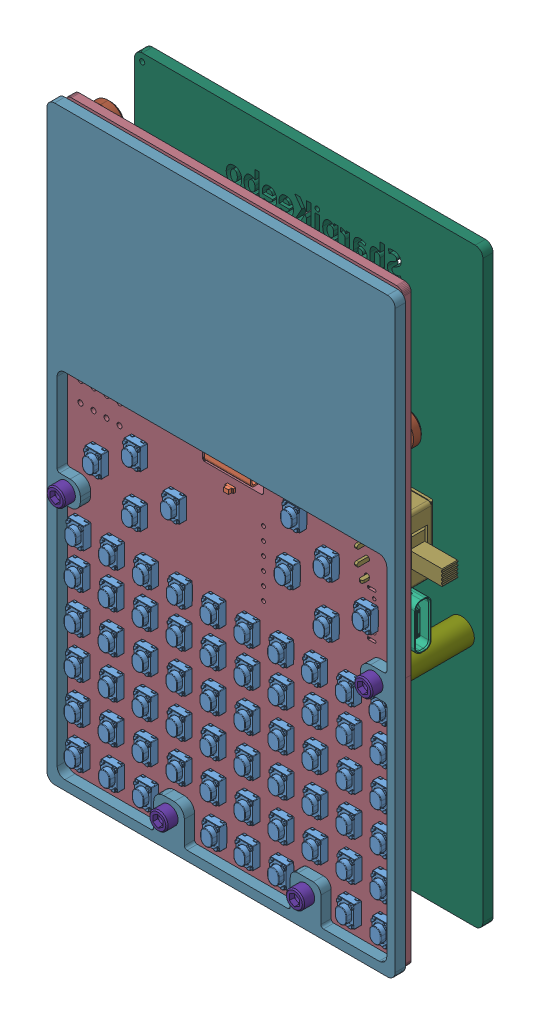
SolidWorks assembly pcbframe, configuration Défaut. Lengths in mm.
Overall size (72.24 115.41 21.31).
366 component instances, 20 part files, 22 mates.
Components (placement in the parent):
- pcbframe.STEP-1: pcbframe.STEP [Défaut] at origin size (71.24 115.32 9.7)
  - pcbframe.step.STEP-1: pcbframe.step.STEP [Défaut] at origin size (71.24 115.32 9.7)
    - SKRPABE010.step.STEP-1: SKRPABE010.step.STEP [Défaut] at (152.039 -127.29 1.65) x (0 1 0) z (1 0 0) size (4.6 2.5 3.2)
      - SOLID.step.STEP-1: SOLID.step.STEP [Défaut] at origin size (4.6 2.5 3.2)
    - SKRPABE010.step.STEP-2: SKRPABE010.step.STEP [Défaut] at (158.671 -127.29 1.65) x (0 1 0) z (1 0 0) size (4.6 2.5 3.2)
      - SOLID.step.STEP-1: SOLID.step.STEP [Défaut] at origin size (4.6 2.5 3.2)
    - SKRPABE010.step.STEP-3: SKRPABE010.step.STEP [Défaut] at (165.303 -127.29 1.65) x (0 1 0) z (1 0 0) size (4.6 2.5 3.2)
      - SOLID.step.STEP-1: SOLID.step.STEP [Défaut] at origin size (4.6 2.5 3.2)
    - SKRPABE010.step.STEP-4: SKRPABE010.step.STEP [Défaut] at (171.936 -127.29 1.65) x (0 1 0) z (1 0 0) size (4.6 2.5 3.2)
      - SOLID.step.STEP-1: SOLID.step.STEP [Défaut] at origin size (4.6 2.5 3.2)
    - SKRPABE010.step.STEP-5: SKRPABE010.step.STEP [Défaut] at (178.568 -127.29 1.65) x (0 1 0) z (1 0 0) size (4.6 2.5 3.2)
      - SOLID.step.STEP-1: SOLID.step.STEP [Défaut] at origin size (4.6 2.5 3.2)
    - SKRPABE010.step.STEP-6: SKRPABE010.step.STEP [Défaut] at (185.2 -127.29 1.65) x (0 1 0) z (1 0 0) size (4.6 2.5 3.2)
      - SOLID.step.STEP-1: SOLID.step.STEP [Défaut] at origin size (4.6 2.5 3.2)
    - SKRPABE010.step.STEP-7: SKRPABE010.step.STEP [Défaut] at (191.832 -127.29 1.65) x (0 1 0) z (1 0 0) size (4.6 2.5 3.2)
      - SOLID.step.STEP-1: SOLID.step.STEP [Défaut] at origin size (4.6 2.5 3.2)
    - SKRPABE010.step.STEP-8: SKRPABE010.step.STEP [Défaut] at (198.465 -127.29 1.65) x (0 1 0) z (1 0 0) size (4.6 2.5 3.2)
      - SOLID.step.STEP-1: SOLID.step.STEP [Défaut] at origin size (4.6 2.5 3.2)
    - SKRPABE010.step.STEP-9: SKRPABE010.step.STEP [Défaut] at (205.097 -127.29 1.65) x (0 1 0) z (1 0 0) size (4.6 2.5 3.2)
      - SOLID.step.STEP-1: SOLID.step.STEP [Défaut] at origin size (4.6 2.5 3.2)
    - SKRPABE010.step.STEP-10: SKRPABE010.step.STEP [Défaut] at (200.68 -101.255 1.65) x (0 1 0) z (1 0 0) size (4.6 2.5 3.2)
      - SOLID.step.STEP-1: SOLID.step.STEP [Défaut] at origin size (4.6 2.5 3.2)
    - SKRPABE010.step.STEP-11: SKRPABE010.step.STEP [Défaut] at (200.68 -111.415 1.65) x (0 1 0) z (1 0 0) size (4.6 2.5 3.2)
      - SOLID.step.STEP-1: SOLID.step.STEP [Défaut] at origin size (4.6 2.5 3.2)
    - SKRPABE010.step.STEP-12: SKRPABE010.step.STEP [Défaut] at (152.039 -134.91 1.65) x (0 1 0) z (1 0 0) size (4.6 2.5 3.2)
      - SOLID.step.STEP-1: SOLID.step.STEP [Défaut] at origin size (4.6 2.5 3.2)
    - SKRPABE010.step.STEP-13: SKRPABE010.step.STEP [Défaut] at (158.671 -134.91 1.65) x (0 1 0) z (1 0 0) size (4.6 2.5 3.2)
      - SOLID.step.STEP-1: SOLID.step.STEP [Défaut] at origin size (4.6 2.5 3.2)
    - SKRPABE010.step.STEP-14: SKRPABE010.step.STEP [Défaut] at (165.303 -134.91 1.65) x (0 1 0) z (1 0 0) size (4.6 2.5 3.2)
      - SOLID.step.STEP-1: SOLID.step.STEP [Défaut] at origin size (4.6 2.5 3.2)
    - SKRPABE010.step.STEP-15: SKRPABE010.step.STEP [Défaut] at (171.936 -134.91 1.65) x (0 1 0) z (1 0 0) size (4.6 2.5 3.2)
      - SOLID.step.STEP-1: SOLID.step.STEP [Défaut] at origin size (4.6 2.5 3.2)
    - SKRPABE010.step.STEP-16: SKRPABE010.step.STEP [Défaut] at (178.568 -134.91 1.65) x (0 1 0) z (1 0 0) size (4.6 2.5 3.2)
      - SOLID.step.STEP-1: SOLID.step.STEP [Défaut] at origin size (4.6 2.5 3.2)
    - SKRPABE010.step.STEP-17: SKRPABE010.step.STEP [Défaut] at (185.2 -134.91 1.65) x (0 1 0) z (1 0 0) size (4.6 2.5 3.2)
      - SOLID.step.STEP-1: SOLID.step.STEP [Défaut] at origin size (4.6 2.5 3.2)
    - SKRPABE010.step.STEP-18: SKRPABE010.step.STEP [Défaut] at (191.832 -134.91 1.65) x (0 1 0) z (1 0 0) size (4.6 2.5 3.2)
      - SOLID.step.STEP-1: SOLID.step.STEP [Défaut] at origin size (4.6 2.5 3.2)
    - SKRPABE010.step.STEP-19: SKRPABE010.step.STEP [Défaut] at (198.465 -134.91 1.65) x (0 1 0) z (1 0 0) size (4.6 2.5 3.2)
      - SOLID.step.STEP-1: SOLID.step.STEP [Défaut] at origin size (4.6 2.5 3.2)
    - SKRPABE010.step.STEP-20: SKRPABE010.step.STEP [Défaut] at (205.097 -134.91 1.65) x (0 1 0) z (1 0 0) size (4.6 2.5 3.2)
      - SOLID.step.STEP-1: SOLID.step.STEP [Défaut] at origin size (4.6 2.5 3.2)
    - SKRPABE010.step.STEP-21: SKRPABE010.step.STEP [Défaut] at (211.729 -134.91 1.65) x (0 1 0) z (1 0 0) size (4.6 2.5 3.2)
      - SOLID.step.STEP-1: SOLID.step.STEP [Défaut] at origin size (4.6 2.5 3.2)
    - SKRPABE010.step.STEP-22: SKRPABE010.step.STEP [Défaut] at (193.06 -106.335 1.65) x (0 1 0) z (1 0 0) size (4.6 2.5 3.2)
      - SOLID.step.STEP-1: SOLID.step.STEP [Défaut] at origin size (4.6 2.5 3.2)
    - SKRPABE010.step.STEP-23: SKRPABE010.step.STEP [Défaut] at (208.3 -106.335 1.65) x (0 1 0) z (1 0 0) size (4.6 2.5 3.2)
      - SOLID.step.STEP-1: SOLID.step.STEP [Défaut] at origin size (4.6 2.5 3.2)
    - SKRPABE010.step.STEP-24: SKRPABE010.step.STEP [Défaut] at (152.039 -142.53 1.65) x (0 1 0) z (1 0 0) size (4.6 2.5 3.2)
      - SOLID.step.STEP-1: SOLID.step.STEP [Défaut] at origin size (4.6 2.5 3.2)
    - SKRPABE010.step.STEP-25: SKRPABE010.step.STEP [Défaut] at (158.671 -142.53 1.65) x (0 1 0) z (1 0 0) size (4.6 2.5 3.2)
      - SOLID.step.STEP-1: SOLID.step.STEP [Défaut] at origin size (4.6 2.5 3.2)
    - SKRPABE010.step.STEP-26: SKRPABE010.step.STEP [Défaut] at (165.303 -142.53 1.65) x (0 1 0) z (1 0 0) size (4.6 2.5 3.2)
      - SOLID.step.STEP-1: SOLID.step.STEP [Défaut] at origin size (4.6 2.5 3.2)
    - SKRPABE010.step.STEP-27: SKRPABE010.step.STEP [Défaut] at (171.936 -142.53 1.65) x (0 1 0) z (1 0 0) size (4.6 2.5 3.2)
      - SOLID.step.STEP-1: SOLID.step.STEP [Défaut] at origin size (4.6 2.5 3.2)
    - SKRPABE010.step.STEP-28: SKRPABE010.step.STEP [Défaut] at (185.2 -142.53 1.65) x (0 1 0) z (1 0 0) size (4.6 2.5 3.2)
      - SOLID.step.STEP-1: SOLID.step.STEP [Défaut] at origin size (4.6 2.5 3.2)
    - SKRPABE010.step.STEP-29: SKRPABE010.step.STEP [Défaut] at (191.832 -142.53 1.65) x (0 1 0) z (1 0 0) size (4.6 2.5 3.2)
      - SOLID.step.STEP-1: SOLID.step.STEP [Défaut] at origin size (4.6 2.5 3.2)
    - SKRPABE010.step.STEP-30: SKRPABE010.step.STEP [Défaut] at (198.465 -142.53 1.65) x (0 1 0) z (1 0 0) size (4.6 2.5 3.2)
      - SOLID.step.STEP-1: SOLID.step.STEP [Défaut] at origin size (4.6 2.5 3.2)
    - SKRPABE010.step.STEP-31: SKRPABE010.step.STEP [Défaut] at (205.097 -142.53 1.65) x (0 1 0) z (1 0 0) size (4.6 2.5 3.2)
      - SOLID.step.STEP-1: SOLID.step.STEP [Défaut] at origin size (4.6 2.5 3.2)
    - SKRPABE010.step.STEP-32: SKRPABE010.step.STEP [Défaut] at (211.729 -142.53 1.65) x (0 1 0) z (1 0 0) size (4.6 2.5 3.2)
      - SOLID.step.STEP-1: SOLID.step.STEP [Défaut] at origin size (4.6 2.5 3.2)
    - SKRPABE010.step.STEP-33: SKRPABE010.step.STEP [Défaut] at (185.186 -120.178 1.65) x (0 1 0) z (1 0 0) size (4.6 2.5 3.2)
      - SOLID.step.STEP-1: SOLID.step.STEP [Défaut] at origin size (4.6 2.5 3.2)
    - SKRPABE010.step.STEP-34: SKRPABE010.step.STEP [Défaut] at (191.79 -120.178 1.65) x (0 1 0) z (1 0 0) size (4.6 2.5 3.2)
      - SOLID.step.STEP-1: SOLID.step.STEP [Défaut] at origin size (4.6 2.5 3.2)
    - SKRPABE010.step.STEP-35: SKRPABE010.step.STEP [Défaut] at (152.039 -150.15 1.65) x (0 1 0) z (1 0 0) size (4.6 2.5 3.2)
      - SOLID.step.STEP-1: SOLID.step.STEP [Défaut] at origin size (4.6 2.5 3.2)
    - SKRPABE010.step.STEP-36: SKRPABE010.step.STEP [Défaut] at (158.671 -150.15 1.65) x (0 1 0) z (1 0 0) size (4.6 2.5 3.2)
      - SOLID.step.STEP-1: SOLID.step.STEP [Défaut] at origin size (4.6 2.5 3.2)
    - SKRPABE010.step.STEP-37: SKRPABE010.step.STEP [Défaut] at (165.303 -150.15 1.65) x (0 1 0) z (1 0 0) size (4.6 2.5 3.2)
      - SOLID.step.STEP-1: SOLID.step.STEP [Défaut] at origin size (4.6 2.5 3.2)
    - SKRPABE010.step.STEP-38: SKRPABE010.step.STEP [Défaut] at (171.936 -150.15 1.65) x (0 1 0) z (1 0 0) size (4.6 2.5 3.2)
      - SOLID.step.STEP-1: SOLID.step.STEP [Défaut] at origin size (4.6 2.5 3.2)
    - SKRPABE010.step.STEP-39: SKRPABE010.step.STEP [Défaut] at (178.568 -150.15 1.65) x (0 1 0) z (1 0 0) size (4.6 2.5 3.2)
      - SOLID.step.STEP-1: SOLID.step.STEP [Défaut] at origin size (4.6 2.5 3.2)
    - SKRPABE010.step.STEP-40: SKRPABE010.step.STEP [Défaut] at (185.2 -150.15 1.65) x (0 1 0) z (1 0 0) size (4.6 2.5 3.2)
      - SOLID.step.STEP-1: SOLID.step.STEP [Défaut] at origin size (4.6 2.5 3.2)
    - SKRPABE010.step.STEP-41: SKRPABE010.step.STEP [Défaut] at (191.832 -150.15 1.65) x (0 1 0) z (1 0 0) size (4.6 2.5 3.2)
      - SOLID.step.STEP-1: SOLID.step.STEP [Défaut] at origin size (4.6 2.5 3.2)
    - SKRPABE010.step.STEP-42: SKRPABE010.step.STEP [Défaut] at (198.465 -150.15 1.65) x (0 1 0) z (1 0 0) size (4.6 2.5 3.2)
      - SOLID.step.STEP-1: SOLID.step.STEP [Défaut] at origin size (4.6 2.5 3.2)
    - SKRPABE010.step.STEP-43: SKRPABE010.step.STEP [Défaut] at (205.097 -150.15 1.65) x (0 1 0) z (1 0 0) size (4.6 2.5 3.2)
      - SOLID.step.STEP-1: SOLID.step.STEP [Défaut] at origin size (4.6 2.5 3.2)
    - SKRPABE010.step.STEP-44: SKRPABE010.step.STEP [Défaut] at (211.729 -150.15 1.65) x (0 1 0) z (1 0 0) size (4.6 2.5 3.2)
      - SOLID.step.STEP-1: SOLID.step.STEP [Défaut] at origin size (4.6 2.5 3.2)
    - SKRPABE010.step.STEP-45: SKRPABE010.step.STEP [Défaut] at (198.394 -120.178 1.65) x (0 1 0) z (1 0 0) size (4.6 2.5 3.2)
      - SOLID.step.STEP-1: SOLID.step.STEP [Défaut] at origin size (4.6 2.5 3.2)
    - SKRPABE010.step.STEP-46: SKRPABE010.step.STEP [Défaut] at (204.998 -120.178 1.65) x (0 1 0) z (1 0 0) size (4.6 2.5 3.2)
      - SOLID.step.STEP-1: SOLID.step.STEP [Défaut] at origin size (4.6 2.5 3.2)
    - SKRPABE010.step.STEP-47: SKRPABE010.step.STEP [Défaut] at (152.039 -157.77 1.65) x (0 1 0) z (1 0 0) size (4.6 2.5 3.2)
      - SOLID.step.STEP-1: SOLID.step.STEP [Défaut] at origin size (4.6 2.5 3.2)
    - SKRPABE010.step.STEP-48: SKRPABE010.step.STEP [Défaut] at (158.77 -157.77 1.65) x (0 1 0) z (1 0 0) size (4.6 2.5 3.2)
      - SOLID.step.STEP-1: SOLID.step.STEP [Défaut] at origin size (4.6 2.5 3.2)
    - SKRPABE010.step.STEP-49: SKRPABE010.step.STEP [Défaut] at (165.374 -157.77 1.65) x (0 1 0) z (1 0 0) size (4.6 2.5 3.2)
      - SOLID.step.STEP-1: SOLID.step.STEP [Défaut] at origin size (4.6 2.5 3.2)
    - SKRPABE010.step.STEP-50: SKRPABE010.step.STEP [Défaut] at (178.709 -157.77 1.65) x (0 1 0) z (1 0 0) size (4.6 2.5 3.2)
      - SOLID.step.STEP-1: SOLID.step.STEP [Défaut] at origin size (4.6 2.5 3.2)
    - SKRPABE010.step.STEP-51: SKRPABE010.step.STEP [Défaut] at (185.186 -157.77 1.65) x (0 1 0) z (1 0 0) size (4.6 2.5 3.2)
      - SOLID.step.STEP-1: SOLID.step.STEP [Défaut] at origin size (4.6 2.5 3.2)
    - SKRPABE010.step.STEP-52: SKRPABE010.step.STEP [Défaut] at (191.79 -157.77 1.65) x (0 1 0) z (1 0 0) size (4.6 2.5 3.2)
      - SOLID.step.STEP-1: SOLID.step.STEP [Défaut] at origin size (4.6 2.5 3.2)
    - SKRPABE010.step.STEP-53: SKRPABE010.step.STEP [Défaut] at (211.729 -157.77 1.65) x (0 1 0) z (1 0 0) size (4.6 2.5 3.2)
      - SOLID.step.STEP-1: SOLID.step.STEP [Défaut] at origin size (4.6 2.5 3.2)
    - SKRPABE010.step.STEP-54: SKRPABE010.step.STEP [Défaut] at (211.602 -120.178 1.65) x (0 1 0) z (1 0 0) size (4.6 2.5 3.2)
      - SOLID.step.STEP-1: SOLID.step.STEP [Défaut] at origin size (4.6 2.5 3.2)
    - SKRPABE010.step.STEP-55: SKRPABE010.step.STEP [Défaut] at (152.166 -120.178 1.65) x (0 1 0) z (1 0 0) size (4.6 2.5 3.2)
      - SOLID.step.STEP-1: SOLID.step.STEP [Défaut] at origin size (4.6 2.5 3.2)
    - SKRPABE010.step.STEP-56: SKRPABE010.step.STEP [Défaut] at (158.77 -120.178 1.65) x (0 1 0) z (1 0 0) size (4.6 2.5 3.2)
      - SOLID.step.STEP-1: SOLID.step.STEP [Défaut] at origin size (4.6 2.5 3.2)
    - SKRPABE010.step.STEP-57: SKRPABE010.step.STEP [Défaut] at (165.374 -120.178 1.65) x (0 1 0) z (1 0 0) size (4.6 2.5 3.2)
      - SOLID.step.STEP-1: SOLID.step.STEP [Défaut] at origin size (4.6 2.5 3.2)
    - SKRPABE010.step.STEP-58: SKRPABE010.step.STEP [Défaut] at (171.978 -120.178 1.65) x (0 1 0) z (1 0 0) size (4.6 2.5 3.2)
      - SOLID.step.STEP-1: SOLID.step.STEP [Défaut] at origin size (4.6 2.5 3.2)
    - SKRPABE010.step.STEP-59: SKRPABE010.step.STEP [Défaut] at (178.582 -120.178 1.65) x (0 1 0) z (1 0 0) size (4.6 2.5 3.2)
      - SOLID.step.STEP-1: SOLID.step.STEP [Défaut] at origin size (4.6 2.5 3.2)
    - SKRPABE010.step.STEP-60: SKRPABE010.step.STEP [Défaut] at (211.729 -127.29 1.65) x (0 1 0) z (1 0 0) size (4.6 2.5 3.2)
      - SOLID.step.STEP-1: SOLID.step.STEP [Défaut] at origin size (4.6 2.5 3.2)
    - SKRPABE010.step.STEP-61: SKRPABE010.step.STEP [Défaut] at (204.998 -157.77 1.65) x (0 1 0) z (1 0 0) size (4.6 2.5 3.2)
      - SOLID.step.STEP-1: SOLID.step.STEP [Défaut] at origin size (4.6 2.5 3.2)
    - SKRPABE010.step.STEP-62: SKRPABE010.step.STEP [Défaut] at (178.568 -142.53 1.65) x (0 1 0) z (1 0 0) size (4.6 2.5 3.2)
      - SOLID.step.STEP-1: SOLID.step.STEP [Défaut] at origin size (4.6 2.5 3.2)
    - SKRPABE010.step.STEP-63: SKRPABE010.step.STEP [Défaut] at (194.33 -96.048 1.65) x (0 1 0) z (1 0 0) size (4.6 2.5 3.2)
      - SOLID.step.STEP-1: SOLID.step.STEP [Défaut] at origin size (4.6 2.5 3.2)
    - SKRPABE010.step.STEP-64: SKRPABE010.step.STEP [Défaut] at (155.595 -106.335 1.65) x (0 1 0) z (1 0 0) size (4.6 2.5 3.2)
      - SOLID.step.STEP-1: SOLID.step.STEP [Défaut] at origin size (4.6 2.5 3.2)
    - SKRPABE010.step.STEP-65: SKRPABE010.step.STEP [Défaut] at (163.215 -111.415 1.65) x (0 1 0) z (1 0 0) size (4.6 2.5 3.2)
      - SOLID.step.STEP-1: SOLID.step.STEP [Défaut] at origin size (4.6 2.5 3.2)
    - SKRPABE010.step.STEP-66: SKRPABE010.step.STEP [Défaut] at (163.215 -101.255 1.65) x (0 1 0) z (1 0 0) size (4.6 2.5 3.2)
      - SOLID.step.STEP-1: SOLID.step.STEP [Défaut] at origin size (4.6 2.5 3.2)
    - SKRPABE010.step.STEP-67: SKRPABE010.step.STEP [Défaut] at (170.835 -106.335 1.65) x (0 1 0) z (1 0 0) size (4.6 2.5 3.2)
      - SOLID.step.STEP-1: SOLID.step.STEP [Défaut] at origin size (4.6 2.5 3.2)
    - LED_0603_1608Metric.step.STEP-1: LED_0603_1608Metric.step.STEP [Défaut] at (181.204 -98.4885 1.65) size (1.6 0.8 1.1)
      - SOLID-0.step.STEP-1: SOLID-0.step.STEP [Défaut] at origin size (1.6 0.8 1.1)
    - C_0603_1608Metric.step.STEP-1: C_0603_1608Metric.step.STEP [Défaut] at (185.42 -81.915 -0.05) x (0 1 0) z (0 0 -1) size (1.6 0.8 0.8)
      - SOLID-1.step.STEP-1: SOLID-1.step.STEP [Défaut] at origin size (1.6 0.8 0.8)
    - C_0603_1608Metric.step.STEP-2: C_0603_1608Metric.step.STEP [Défaut] at (181.61 -81.915 -0.05) x (0 1 0) z (0 0 -1) size (1.6 0.8 0.8)
      - SOLID-1.step.STEP-1: SOLID-1.step.STEP [Défaut] at origin size (1.6 0.8 0.8)
    - C_0603_1608Metric.step.STEP-3: C_0603_1608Metric.step.STEP [Défaut] at (179.705 -81.915 -0.05) x (0 1 0) z (0 0 -1) size (1.6 0.8 0.8)
      - SOLID-1.step.STEP-1: SOLID-1.step.STEP [Défaut] at origin size (1.6 0.8 0.8)
    - R_0603_1608Metric.step.STEP-1: R_0603_1608Metric.step.STEP [Défaut] at (199.39 -97.7265 -0.05) x (1 0 0) z (0 0 -1) size (1.6 0.8 0.45)
      - SOLID-2.step.STEP-1: SOLID-2.step.STEP [Défaut] at origin size (1.6 0.8 0.45)
    - R_0603_1608Metric.step.STEP-2: R_0603_1608Metric.step.STEP [Défaut] at (195.136 -106.236 -0.05) x (-1 0 0) z (0 0 -1) size (1.6 0.8 0.45)
      - SOLID-2.step.STEP-1: SOLID-2.step.STEP [Défaut] at origin size (1.6 0.8 0.45)
    - R_0603_1608Metric.step.STEP-3: R_0603_1608Metric.step.STEP [Défaut] at (170.284 -95.885 -0.05) x (1 0 0) z (0 0 -1) size (1.6 0.8 0.45)
      - SOLID-2.step.STEP-1: SOLID-2.step.STEP [Défaut] at origin size (1.6 0.8 0.45)
    - R_0603_1608Metric.step.STEP-4: R_0603_1608Metric.step.STEP [Défaut] at (152.34 -106.331 -0.05) x (-1 0 0) z (0 0 -1) size (1.6 0.8 0.45)
      - SOLID-2.step.STEP-1: SOLID-2.step.STEP [Défaut] at origin size (1.6 0.8 0.45)
    - R_0603_1608Metric.step.STEP-5: R_0603_1608Metric.step.STEP [Défaut] at (156.976 -112.872 -0.05) x (-1 0 0) z (0 0 -1) size (1.6 0.8 0.45)
      - SOLID-2.step.STEP-1: SOLID-2.step.STEP [Défaut] at origin size (1.6 0.8 0.45)
    - R_0603_1608Metric.step.STEP-6: R_0603_1608Metric.step.STEP [Défaut] at (156.865 -109.696 -0.05) x (-1 0 0) z (0 0 -1) size (1.6 0.8 0.45)
      - SOLID-2.step.STEP-1: SOLID-2.step.STEP [Défaut] at origin size (1.6 0.8 0.45)
    - R_0603_1608Metric.step.STEP-7: R_0603_1608Metric.step.STEP [Défaut] at (170.18 -93.98 -0.05) x (1 0 0) z (0 0 -1) size (1.6 0.8 0.45)
      - SOLID-2.step.STEP-1: SOLID-2.step.STEP [Défaut] at origin size (1.6 0.8 0.45)
    - R_0603_1608Metric.step.STEP-8: R_0603_1608Metric.step.STEP [Défaut] at (152.467 -103.283 -0.05) x (-1 0 0) z (0 0 -1) size (1.6 0.8 0.45)
      - SOLID-2.step.STEP-1: SOLID-2.step.STEP [Défaut] at origin size (1.6 0.8 0.45)
    - R_0603_1608Metric.step.STEP-9: R_0603_1608Metric.step.STEP [Défaut] at (156.722 -106.268 -0.05) x (-1 0 0) z (0 0 -1) size (1.6 0.8 0.45)
      - SOLID-2.step.STEP-1: SOLID-2.step.STEP [Défaut] at origin size (1.6 0.8 0.45)
    - R_0603_1608Metric.step.STEP-10: R_0603_1608Metric.step.STEP [Défaut] at (156.785 -103.283 -0.05) x (-1 0 0) z (0 0 -1) size (1.6 0.8 0.45)
      - SOLID-2.step.STEP-1: SOLID-2.step.STEP [Défaut] at origin size (1.6 0.8 0.45)
    - C_0603_1608Metric.step.STEP-4: C_0603_1608Metric.step.STEP [Défaut] at (174.219 -51.1556 -0.05) x (0 1 0) z (0 0 -1) size (1.6 0.8 0.8)
      - SOLID-1.step.STEP-1: SOLID-1.step.STEP [Défaut] at origin size (1.6 0.8 0.8)
    - C_0603_1608Metric.step.STEP-5: C_0603_1608Metric.step.STEP [Défaut] at (177.775 -51.1686 -0.05) x (0 1 0) z (0 0 -1) size (1.6 0.8 0.8)
      - SOLID-1.step.STEP-1: SOLID-1.step.STEP [Défaut] at origin size (1.6 0.8 0.8)
    - C_0603_1608Metric.step.STEP-6: C_0603_1608Metric.step.STEP [Défaut] at (152.756 -66.9544 -0.05) x (0 1 0) z (0 0 -1) size (1.6 0.8 0.8)
      - SOLID-1.step.STEP-1: SOLID-1.step.STEP [Défaut] at origin size (1.6 0.8 0.8)
    - C_0603_1608Metric.step.STEP-7: C_0603_1608Metric.step.STEP [Défaut] at (172.441 -51.1686 -0.05) x (0 1 0) z (0 0 -1) size (1.6 0.8 0.8)
      - SOLID-1.step.STEP-1: SOLID-1.step.STEP [Défaut] at origin size (1.6 0.8 0.8)
    - C_0603_1608Metric.step.STEP-8: C_0603_1608Metric.step.STEP [Défaut] at (175.997 -51.1686 -0.05) x (0 1 0) z (0 0 -1) size (1.6 0.8 0.8)
      - SOLID-1.step.STEP-1: SOLID-1.step.STEP [Défaut] at origin size (1.6 0.8 0.8)
    - D_SOD-323.step.STEP-1: D_SOD-323.step.STEP [Défaut] at (151.892 -127.254 -0.05) x (0 -1 0) z (0 0 -1) size (2.5 1.25 1.1)
      - SOLID-3.step.STEP-1: SOLID-3.step.STEP [Défaut] at origin size (2.5 1.25 1.1)
    - D_SOD-323.step.STEP-2: D_SOD-323.step.STEP [Défaut] at (158.496 -127.254 -0.05) x (0 -1 0) z (0 0 -1) size (2.5 1.25 1.1)
      - SOLID-3.step.STEP-1: SOLID-3.step.STEP [Défaut] at origin size (2.5 1.25 1.1)
    - D_SOD-323.step.STEP-3: D_SOD-323.step.STEP [Défaut] at (165.1 -127.254 -0.05) x (0 -1 0) z (0 0 -1) size (2.5 1.25 1.1)
      - SOLID-3.step.STEP-1: SOLID-3.step.STEP [Défaut] at origin size (2.5 1.25 1.1)
    - D_SOD-323.step.STEP-4: D_SOD-323.step.STEP [Défaut] at (171.704 -127.254 -0.05) x (0 -1 0) z (0 0 -1) size (2.5 1.25 1.1)
      - SOLID-3.step.STEP-1: SOLID-3.step.STEP [Défaut] at origin size (2.5 1.25 1.1)
    - D_SOD-323.step.STEP-5: D_SOD-323.step.STEP [Défaut] at (178.308 -127.254 -0.05) x (0 -1 0) z (0 0 -1) size (2.5 1.25 1.1)
      - SOLID-3.step.STEP-1: SOLID-3.step.STEP [Défaut] at origin size (2.5 1.25 1.1)
    - D_SOD-323.step.STEP-6: D_SOD-323.step.STEP [Défaut] at (185.166 -127.254 -0.05) x (0 -1 0) z (0 0 -1) size (2.5 1.25 1.1)
      - SOLID-3.step.STEP-1: SOLID-3.step.STEP [Défaut] at origin size (2.5 1.25 1.1)
    - D_SOD-323.step.STEP-7: D_SOD-323.step.STEP [Défaut] at (191.77 -127.254 -0.05) x (0 -1 0) z (0 0 -1) size (2.5 1.25 1.1)
      - SOLID-3.step.STEP-1: SOLID-3.step.STEP [Défaut] at origin size (2.5 1.25 1.1)
    - D_SOD-323.step.STEP-8: D_SOD-323.step.STEP [Défaut] at (198.374 -127.254 -0.05) x (0 -1 0) z (0 0 -1) size (2.5 1.25 1.1)
      - SOLID-3.step.STEP-1: SOLID-3.step.STEP [Défaut] at origin size (2.5 1.25 1.1)
    - D_SOD-323.step.STEP-9: D_SOD-323.step.STEP [Défaut] at (204.978 -127.254 -0.05) x (0 -1 0) z (0 0 -1) size (2.5 1.25 1.1)
      - SOLID-3.step.STEP-1: SOLID-3.step.STEP [Défaut] at origin size (2.5 1.25 1.1)
    - D_SOD-323.step.STEP-10: D_SOD-323.step.STEP [Défaut] at (211.582 -127.274 -0.05) x (0 -1 0) z (0 0 -1) size (2.5 1.25 1.1)
      - SOLID-3.step.STEP-1: SOLID-3.step.STEP [Défaut] at origin size (2.5 1.25 1.1)
    - D_SOD-323.step.STEP-11: D_SOD-323.step.STEP [Défaut] at (206.946 -114.18 -0.05) x (0 -1 0) z (0 0 -1) size (2.5 1.25 1.1)
      - SOLID-3.step.STEP-1: SOLID-3.step.STEP [Défaut] at origin size (2.5 1.25 1.1)
    - D_SOD-323.step.STEP-12: D_SOD-323.step.STEP [Défaut] at (202.374 -114.216 -0.05) x (0 -1 0) z (0 0 -1) size (2.5 1.25 1.1)
      - SOLID-3.step.STEP-1: SOLID-3.step.STEP [Défaut] at origin size (2.5 1.25 1.1)
    - D_SOD-323.step.STEP-13: D_SOD-323.step.STEP [Défaut] at (151.892 -134.874 -0.05) x (0 -1 0) z (0 0 -1) size (2.5 1.25 1.1)
      - SOLID-3.step.STEP-1: SOLID-3.step.STEP [Défaut] at origin size (2.5 1.25 1.1)
    - D_SOD-323.step.STEP-14: D_SOD-323.step.STEP [Défaut] at (158.496 -134.874 -0.05) x (0 -1 0) z (0 0 -1) size (2.5 1.25 1.1)
      - SOLID-3.step.STEP-1: SOLID-3.step.STEP [Défaut] at origin size (2.5 1.25 1.1)
    - D_SOD-323.step.STEP-15: D_SOD-323.step.STEP [Défaut] at (165.1 -134.874 -0.05) x (0 -1 0) z (0 0 -1) size (2.5 1.25 1.1)
      - SOLID-3.step.STEP-1: SOLID-3.step.STEP [Défaut] at origin size (2.5 1.25 1.1)
    - D_SOD-323.step.STEP-16: D_SOD-323.step.STEP [Défaut] at (171.704 -134.874 -0.05) x (0 -1 0) z (0 0 -1) size (2.5 1.25 1.1)
      - SOLID-3.step.STEP-1: SOLID-3.step.STEP [Défaut] at origin size (2.5 1.25 1.1)
    - D_SOD-323.step.STEP-17: D_SOD-323.step.STEP [Défaut] at (178.562 -134.874 -0.05) x (0 -1 0) z (0 0 -1) size (2.5 1.25 1.1)
      - SOLID-3.step.STEP-1: SOLID-3.step.STEP [Défaut] at origin size (2.5 1.25 1.1)
    - D_SOD-323.step.STEP-18: D_SOD-323.step.STEP [Défaut] at (185.166 -134.874 -0.05) x (0 -1 0) z (0 0 -1) size (2.5 1.25 1.1)
      - SOLID-3.step.STEP-1: SOLID-3.step.STEP [Défaut] at origin size (2.5 1.25 1.1)
    - D_SOD-323.step.STEP-19: D_SOD-323.step.STEP [Défaut] at (191.516 -134.874 -0.05) x (0 -1 0) z (0 0 -1) size (2.5 1.25 1.1)
      - SOLID-3.step.STEP-1: SOLID-3.step.STEP [Défaut] at origin size (2.5 1.25 1.1)
    - D_SOD-323.step.STEP-20: D_SOD-323.step.STEP [Défaut] at (198.374 -134.874 -0.05) x (0 -1 0) z (0 0 -1) size (2.5 1.25 1.1)
      - SOLID-3.step.STEP-1: SOLID-3.step.STEP [Défaut] at origin size (2.5 1.25 1.1)
    - D_SOD-323.step.STEP-21: D_SOD-323.step.STEP [Défaut] at (204.978 -134.874 -0.05) x (0 -1 0) z (0 0 -1) size (2.5 1.25 1.1)
      - SOLID-3.step.STEP-1: SOLID-3.step.STEP [Défaut] at origin size (2.5 1.25 1.1)
    - D_SOD-323.step.STEP-22: D_SOD-323.step.STEP [Défaut] at (211.582 -134.874 -0.05) x (0 -1 0) z (0 0 -1) size (2.5 1.25 1.1)
      - SOLID-3.step.STEP-1: SOLID-3.step.STEP [Défaut] at origin size (2.5 1.25 1.1)
    - D_SOD-323.step.STEP-23: D_SOD-323.step.STEP [Défaut] at (197.866 -114.18 -0.05) x (0 -1 0) z (0 0 -1) size (2.5 1.25 1.1)
      - SOLID-3.step.STEP-1: SOLID-3.step.STEP [Défaut] at origin size (2.5 1.25 1.1)
    - D_SOD-323.step.STEP-24: D_SOD-323.step.STEP [Défaut] at (192.024 -114.18 -0.05) x (0 -1 0) z (0 0 -1) size (2.5 1.25 1.1)
      - SOLID-3.step.STEP-1: SOLID-3.step.STEP [Défaut] at origin size (2.5 1.25 1.1)
    - D_SOD-323.step.STEP-25: D_SOD-323.step.STEP [Défaut] at (151.892 -142.494 -0.05) x (0 -1 0) z (0 0 -1) size (2.5 1.25 1.1)
      - SOLID-3.step.STEP-1: SOLID-3.step.STEP [Défaut] at origin size (2.5 1.25 1.1)
    - D_SOD-323.step.STEP-26: D_SOD-323.step.STEP [Défaut] at (158.496 -142.494 -0.05) x (0 -1 0) z (0 0 -1) size (2.5 1.25 1.1)
      - SOLID-3.step.STEP-1: SOLID-3.step.STEP [Défaut] at origin size (2.5 1.25 1.1)
    - D_SOD-323.step.STEP-27: D_SOD-323.step.STEP [Défaut] at (165.1 -142.494 -0.05) x (0 -1 0) z (0 0 -1) size (2.5 1.25 1.1)
      - SOLID-3.step.STEP-1: SOLID-3.step.STEP [Défaut] at origin size (2.5 1.25 1.1)
    - D_SOD-323.step.STEP-28: D_SOD-323.step.STEP [Défaut] at (171.704 -142.494 -0.05) x (0 -1 0) z (0 0 -1) size (2.5 1.25 1.1)
      - SOLID-3.step.STEP-1: SOLID-3.step.STEP [Défaut] at origin size (2.5 1.25 1.1)
    - D_SOD-323.step.STEP-29: D_SOD-323.step.STEP [Défaut] at (178.562 -142.494 -0.05) x (0 -1 0) z (0 0 -1) size (2.5 1.25 1.1)
      - SOLID-3.step.STEP-1: SOLID-3.step.STEP [Défaut] at origin size (2.5 1.25 1.1)
    - D_SOD-323.step.STEP-30: D_SOD-323.step.STEP [Défaut] at (184.912 -142.494 -0.05) x (0 -1 0) z (0 0 -1) size (2.5 1.25 1.1)
      - SOLID-3.step.STEP-1: SOLID-3.step.STEP [Défaut] at origin size (2.5 1.25 1.1)
    - D_SOD-323.step.STEP-31: D_SOD-323.step.STEP [Défaut] at (191.77 -142.494 -0.05) x (0 -1 0) z (0 0 -1) size (2.5 1.25 1.1)
      - SOLID-3.step.STEP-1: SOLID-3.step.STEP [Défaut] at origin size (2.5 1.25 1.1)
    - D_SOD-323.step.STEP-32: D_SOD-323.step.STEP [Défaut] at (198.12 -142.494 -0.05) x (0 -1 0) z (0 0 -1) size (2.5 1.25 1.1)
      - SOLID-3.step.STEP-1: SOLID-3.step.STEP [Défaut] at origin size (2.5 1.25 1.1)
    - D_SOD-323.step.STEP-33: D_SOD-323.step.STEP [Défaut] at (204.978 -142.494 -0.05) x (0 -1 0) z (0 0 -1) size (2.5 1.25 1.1)
      - SOLID-3.step.STEP-1: SOLID-3.step.STEP [Défaut] at origin size (2.5 1.25 1.1)
    - D_SOD-323.step.STEP-34: D_SOD-323.step.STEP [Défaut] at (211.582 -142.494 -0.05) x (0 -1 0) z (0 0 -1) size (2.5 1.25 1.1)
      - SOLID-3.step.STEP-1: SOLID-3.step.STEP [Défaut] at origin size (2.5 1.25 1.1)
    - D_SOD-323.step.STEP-35: D_SOD-323.step.STEP [Défaut] at (185.166 -120.142 -0.05) x (0 -1 0) z (0 0 -1) size (2.5 1.25 1.1)
      - SOLID-3.step.STEP-1: SOLID-3.step.STEP [Défaut] at origin size (2.5 1.25 1.1)
    - D_SOD-323.step.STEP-36: D_SOD-323.step.STEP [Défaut] at (191.77 -120.142 -0.05) x (0 -1 0) z (0 0 -1) size (2.5 1.25 1.1)
      - SOLID-3.step.STEP-1: SOLID-3.step.STEP [Défaut] at origin size (2.5 1.25 1.1)
    - D_SOD-323.step.STEP-37: D_SOD-323.step.STEP [Défaut] at (151.892 -150.114 -0.05) x (0 -1 0) z (0 0 -1) size (2.5 1.25 1.1)
      - SOLID-3.step.STEP-1: SOLID-3.step.STEP [Défaut] at origin size (2.5 1.25 1.1)
    - D_SOD-323.step.STEP-38: D_SOD-323.step.STEP [Défaut] at (158.75 -150.114 -0.05) x (0 -1 0) z (0 0 -1) size (2.5 1.25 1.1)
      - SOLID-3.step.STEP-1: SOLID-3.step.STEP [Défaut] at origin size (2.5 1.25 1.1)
    - D_SOD-323.step.STEP-39: D_SOD-323.step.STEP [Défaut] at (165.1 -150.114 -0.05) x (0 -1 0) z (0 0 -1) size (2.5 1.25 1.1)
      - SOLID-3.step.STEP-1: SOLID-3.step.STEP [Défaut] at origin size (2.5 1.25 1.1)
    - D_SOD-323.step.STEP-40: D_SOD-323.step.STEP [Défaut] at (171.958 -150.114 -0.05) x (0 -1 0) z (0 0 -1) size (2.5 1.25 1.1)
      - SOLID-3.step.STEP-1: SOLID-3.step.STEP [Défaut] at origin size (2.5 1.25 1.1)
    - D_SOD-323.step.STEP-41: D_SOD-323.step.STEP [Défaut] at (178.308 -150.114 -0.05) x (0 -1 0) z (0 0 -1) size (2.5 1.25 1.1)
      - SOLID-3.step.STEP-1: SOLID-3.step.STEP [Défaut] at origin size (2.5 1.25 1.1)
    - D_SOD-323.step.STEP-42: D_SOD-323.step.STEP [Défaut] at (185.166 -150.114 -0.05) x (0 -1 0) z (0 0 -1) size (2.5 1.25 1.1)
      - SOLID-3.step.STEP-1: SOLID-3.step.STEP [Défaut] at origin size (2.5 1.25 1.1)
    - D_SOD-323.step.STEP-43: D_SOD-323.step.STEP [Défaut] at (191.77 -150.114 -0.05) x (0 -1 0) z (0 0 -1) size (2.5 1.25 1.1)
      - SOLID-3.step.STEP-1: SOLID-3.step.STEP [Défaut] at origin size (2.5 1.25 1.1)
    - D_SOD-323.step.STEP-44: D_SOD-323.step.STEP [Défaut] at (198.374 -150.114 -0.05) x (0 -1 0) z (0 0 -1) size (2.5 1.25 1.1)
      - SOLID-3.step.STEP-1: SOLID-3.step.STEP [Défaut] at origin size (2.5 1.25 1.1)
    - D_SOD-323.step.STEP-45: D_SOD-323.step.STEP [Défaut] at (204.978 -150.114 -0.05) x (0 -1 0) z (0 0 -1) size (2.5 1.25 1.1)
      - SOLID-3.step.STEP-1: SOLID-3.step.STEP [Défaut] at origin size (2.5 1.25 1.1)
    - D_SOD-323.step.STEP-46: D_SOD-323.step.STEP [Défaut] at (211.836 -150.114 -0.05) x (0 -1 0) z (0 0 -1) size (2.5 1.25 1.1)
      - SOLID-3.step.STEP-1: SOLID-3.step.STEP [Défaut] at origin size (2.5 1.25 1.1)
    - D_SOD-323.step.STEP-47: D_SOD-323.step.STEP [Défaut] at (198.374 -120.142 -0.05) x (0 -1 0) z (0 0 -1) size (2.5 1.25 1.1)
      - SOLID-3.step.STEP-1: SOLID-3.step.STEP [Défaut] at origin size (2.5 1.25 1.1)
    - D_SOD-323.step.STEP-48: D_SOD-323.step.STEP [Défaut] at (204.978 -120.142 -0.05) x (0 -1 0) z (0 0 -1) size (2.5 1.25 1.1)
      - SOLID-3.step.STEP-1: SOLID-3.step.STEP [Défaut] at origin size (2.5 1.25 1.1)
    - D_SOD-323.step.STEP-49: D_SOD-323.step.STEP [Défaut] at (151.892 -157.734 -0.05) x (0 -1 0) z (0 0 -1) size (2.5 1.25 1.1)
      - SOLID-3.step.STEP-1: SOLID-3.step.STEP [Défaut] at origin size (2.5 1.25 1.1)
    - D_SOD-323.step.STEP-50: D_SOD-323.step.STEP [Défaut] at (158.75 -157.734 -0.05) x (0 -1 0) z (0 0 -1) size (2.5 1.25 1.1)
      - SOLID-3.step.STEP-1: SOLID-3.step.STEP [Défaut] at origin size (2.5 1.25 1.1)
    - D_SOD-323.step.STEP-51: D_SOD-323.step.STEP [Défaut] at (165.1 -157.734 -0.05) x (0 -1 0) z (0 0 -1) size (2.5 1.25 1.1)
      - SOLID-3.step.STEP-1: SOLID-3.step.STEP [Défaut] at origin size (2.5 1.25 1.1)
    - D_SOD-323.step.STEP-52: D_SOD-323.step.STEP [Défaut] at (178.562 -157.734 -0.05) x (0 -1 0) z (0 0 -1) size (2.5 1.25 1.1)
      - SOLID-3.step.STEP-1: SOLID-3.step.STEP [Défaut] at origin size (2.5 1.25 1.1)
    - D_SOD-323.step.STEP-53: D_SOD-323.step.STEP [Défaut] at (204.978 -157.734 -0.05) x (0 -1 0) z (0 0 -1) size (2.5 1.25 1.1)
      - SOLID-3.step.STEP-1: SOLID-3.step.STEP [Défaut] at origin size (2.5 1.25 1.1)
    - D_SOD-323.step.STEP-54: D_SOD-323.step.STEP [Défaut] at (211.582 -157.734 -0.05) x (0 -1 0) z (0 0 -1) size (2.5 1.25 1.1)
      - SOLID-3.step.STEP-1: SOLID-3.step.STEP [Défaut] at origin size (2.5 1.25 1.1)
    - D_SOD-323.step.STEP-55: D_SOD-323.step.STEP [Défaut] at (211.582 -120.142 -0.05) x (0 -1 0) z (0 0 -1) size (2.5 1.25 1.1)
      - SOLID-3.step.STEP-1: SOLID-3.step.STEP [Défaut] at origin size (2.5 1.25 1.1)
    - D_SOD-323.step.STEP-56: D_SOD-323.step.STEP [Défaut] at (152.146 -120.142 -0.05) x (0 -1 0) z (0 0 -1) size (2.5 1.25 1.1)
      - SOLID-3.step.STEP-1: SOLID-3.step.STEP [Défaut] at origin size (2.5 1.25 1.1)
    - D_SOD-323.step.STEP-57: D_SOD-323.step.STEP [Défaut] at (158.75 -120.142 -0.05) x (0 -1 0) z (0 0 -1) size (2.5 1.25 1.1)
      - SOLID-3.step.STEP-1: SOLID-3.step.STEP [Défaut] at origin size (2.5 1.25 1.1)
    - D_SOD-323.step.STEP-58: D_SOD-323.step.STEP [Défaut] at (165.354 -120.142 -0.05) x (0 -1 0) z (0 0 -1) size (2.5 1.25 1.1)
      - SOLID-3.step.STEP-1: SOLID-3.step.STEP [Défaut] at origin size (2.5 1.25 1.1)
    - D_SOD-323.step.STEP-59: D_SOD-323.step.STEP [Défaut] at (171.958 -120.142 -0.05) x (0 -1 0) z (0 0 -1) size (2.5 1.25 1.1)
      - SOLID-3.step.STEP-1: SOLID-3.step.STEP [Défaut] at origin size (2.5 1.25 1.1)
    - D_SOD-323.step.STEP-60: D_SOD-323.step.STEP [Défaut] at (178.562 -120.142 -0.05) x (0 -1 0) z (0 0 -1) size (2.5 1.25 1.1)
      - SOLID-3.step.STEP-1: SOLID-3.step.STEP [Défaut] at origin size (2.5 1.25 1.1)
    - USB Type C Port (SMD Type).step.STEP-1: USB Type C Port (SMD Type).step.STEP [Défaut] at (208.07 -106.3244 -1.55) x (0 -1 0) z (0 0 1) size (8.94 7.9 4.2)
      - COMPOUND.step.STEP-1: COMPOUND.step.STEP [Défaut] at origin size (8.94 7.9 4.2)
    - R_0603_1608Metric.step.STEP-11: R_0603_1608Metric.step.STEP [Défaut] at (183.553 -57.0992 -0.05) x (1 0 0) z (0 0 -1) size (1.6 0.8 0.45)
      - SOLID-2.step.STEP-1: SOLID-2.step.STEP [Défaut] at origin size (1.6 0.8 0.45)
    - R_0603_1608Metric.step.STEP-12: R_0603_1608Metric.step.STEP [Défaut] at (183.553 -60.1472 -0.05) x (-1 0 0) z (0 0 -1) size (1.6 0.8 0.45)
      - SOLID-2.step.STEP-1: SOLID-2.step.STEP [Défaut] at origin size (1.6 0.8 0.45)
    - R_0603_1608Metric.step.STEP-13: R_0603_1608Metric.step.STEP [Défaut] at (203.797 -102.26 -0.05) x (1 0 0) z (0 0 -1) size (1.6 0.8 0.45)
      - SOLID-2.step.STEP-1: SOLID-2.step.STEP [Défaut] at origin size (1.6 0.8 0.45)
    - R_0603_1608Metric.step.STEP-14: R_0603_1608Metric.step.STEP [Défaut] at (203.796 -103.911 -0.05) x (-1 0 0) z (0 0 -1) size (1.6 0.8 0.45)
      - SOLID-2.step.STEP-1: SOLID-2.step.STEP [Défaut] at origin size (1.6 0.8 0.45)
    - R_0603_1608Metric.step.STEP-15: R_0603_1608Metric.step.STEP [Défaut] at (203.772 -107.886 -0.05) x (1 0 0) z (0 0 -1) size (1.6 0.8 0.45)
      - SOLID-2.step.STEP-1: SOLID-2.step.STEP [Défaut] at origin size (1.6 0.8 0.45)
    - R_0603_1608Metric.step.STEP-16: R_0603_1608Metric.step.STEP [Défaut] at (195.136 -102.044 -0.05) x (-1 0 0) z (0 0 -1) size (1.6 0.8 0.45)
      - SOLID-2.step.STEP-1: SOLID-2.step.STEP [Défaut] at origin size (1.6 0.8 0.45)
    - SW_SPST_B3U-1000P.step.STEP-1: SW_SPST_B3U-1000P.step.STEP [Défaut] at (182.653 -54.102 -0.05) x (-1 0 0) z (0 0 -1) size (4 2.5 1.59)
      - SOLID-4.step.STEP-1: SOLID-4.step.STEP [Défaut] at origin size (4 2.5 1.59)
    - JST-S2B-PH-SM4-TB.step.STEP-1: JST-S2B-PH-SM4-TB.step.STEP [Défaut] at (153.575 -88.09 -0.05) x (0 1 0) z (0 0 -1) size (7.9 8.61 5.61)
      - COMPOUND-5.step.STEP-1: COMPOUND-5.step.STEP [Défaut] at origin size (7.9 8.61 5.61)
    - ATMEGA32U4-MU.step.STEP-1: ATMEGA32U4-MU.step.STEP [Défaut] at (161.734 -59.8805 -0.05) x (0.707107 0.707107 0) z (-0.707107 0.707107 0) size (7 1 7)
      - COMPOUND-6.step.STEP-1: COMPOUND-6.step.STEP [Défaut] at origin size (7 1 7)
    - C_0603_1608Metric.step.STEP-9: C_0603_1608Metric.step.STEP [Défaut] at (209.36 -68.6435 -0.05) x (0 -1 0) z (0 0 -1) size (1.6 0.8 0.8)
      - SOLID-1.step.STEP-1: SOLID-1.step.STEP [Défaut] at origin size (1.6 0.8 0.8)
    - R_0603_1608Metric.step.STEP-17: R_0603_1608Metric.step.STEP [Défaut] at (199.136 -68.326 -0.05) x (1 0 0) z (0 0 -1) size (1.6 0.8 0.45)
      - SOLID-2.step.STEP-1: SOLID-2.step.STEP [Défaut] at origin size (1.6 0.8 0.45)
    - R_0603_1608Metric.step.STEP-18: R_0603_1608Metric.step.STEP [Défaut] at (176.34 -58.674 -0.05) x (1 0 0) z (0 0 -1) size (1.6 0.8 0.45)
      - SOLID-2.step.STEP-1: SOLID-2.step.STEP [Défaut] at origin size (1.6 0.8 0.45)
    - R_0603_1608Metric.step.STEP-19: R_0603_1608Metric.step.STEP [Défaut] at (176.34 -60.325 -0.05) x (1 0 0) z (0 0 -1) size (1.6 0.8 0.45)
      - SOLID-2.step.STEP-1: SOLID-2.step.STEP [Défaut] at origin size (1.6 0.8 0.45)
    - C_0603_1608Metric.step.STEP-10: C_0603_1608Metric.step.STEP [Défaut] at (187.402 -57.0865 -0.05) x (1 0 0) z (0 0 -1) size (1.6 0.8 0.8)
      - SOLID-1.step.STEP-1: SOLID-1.step.STEP [Défaut] at origin size (1.6 0.8 0.8)
    - C_0603_1608Metric.step.STEP-11: C_0603_1608Metric.step.STEP [Défaut] at (187.402 -58.928 -0.05) x (1 0 0) z (0 0 -1) size (1.6 0.8 0.8)
      - SOLID-1.step.STEP-1: SOLID-1.step.STEP [Défaut] at origin size (1.6 0.8 0.8)
    - R_0603_1608Metric.step.STEP-20: R_0603_1608Metric.step.STEP [Défaut] at (170.284 -97.663 -0.05) x (1 0 0) z (0 0 -1) size (1.6 0.8 0.45)
      - SOLID-2.step.STEP-1: SOLID-2.step.STEP [Défaut] at origin size (1.6 0.8 0.45)
    - R_0603_1608Metric.step.STEP-21: R_0603_1608Metric.step.STEP [Défaut] at (168.275 -88.0745 -0.05) x (-1 0 0) z (0 0 -1) size (1.6 0.8 0.45)
      - SOLID-2.step.STEP-1: SOLID-2.step.STEP [Défaut] at origin size (1.6 0.8 0.45)
    - 16mhzcrystal.step.STEP-1: 16mhzcrystal.step.STEP [Défaut] at (156.4549 -55.7489 -0.05) x (0.707107 -0.707107 0) z (0 0 -1) size (1.3 3.2 1)
      - SOLID-7.step.STEP-1: SOLID-7.step.STEP [Défaut] at origin size (1.3 3.2 1)
    - SMTSO-M3-2.step.STEP-1: SMTSO-M3-2.step.STEP [Défaut] at (152.49 -75.74 -0.05) x (1 0 0) z (0 1 0) size (6.3 3.37 6.3)
      - SOLID-8.step.STEP-1: SOLID-8.step.STEP [Défaut] at origin size (6.3 3.37 6.3)
    - SMTSO-M3-2.step.STEP-2: SMTSO-M3-2.step.STEP [Défaut] at (152.52 -52.75 -0.05) x (1 0 0) z (0 1 0) size (6.3 3.37 6.3)
      - SOLID-8.step.STEP-1: SOLID-8.step.STEP [Défaut] at origin size (6.3 3.37 6.3)
    - SMTSO-M3-2.step.STEP-3: SMTSO-M3-2.step.STEP [Défaut] at (210.52 -75.73 -0.05) x (1 0 0) z (0 1 0) size (6.3 3.37 6.3)
      - SOLID-8.step.STEP-1: SOLID-8.step.STEP [Défaut] at origin size (6.3 3.37 6.3)
    - SW_SPST_B3U-1000P.step.STEP-2: SW_SPST_B3U-1000P.step.STEP [Défaut] at (204.343 -68.2625 -0.05) x (-1 0 0) z (0 0 -1) size (4 2.5 1.59)
      - SOLID-4.step.STEP-1: SOLID-4.step.STEP [Défaut] at origin size (4 2.5 1.59)
    - SS12F23.step.STEP-1: SS12F23.step.STEP [Défaut] at (213.33 -94.47 -0.05) x (0 -1 0) z (1 0 0) size (13 9.1 12.9)
      - COMPOUND-9.step.STEP-1: COMPOUND-9.step.STEP [Défaut] at origin size (13 9.1 12.9)
    - R_0603_1608Metric.step.STEP-22: R_0603_1608Metric.step.STEP [Défaut] at (164.084 -92.456 -0.05) x (1 0 0) z (0 0 -1) size (1.6 0.8 0.45)
      - SOLID-2.step.STEP-1: SOLID-2.step.STEP [Défaut] at origin size (1.6 0.8 0.45)
    - R_0603_1608Metric.step.STEP-23: R_0603_1608Metric.step.STEP [Défaut] at (164.4904 -82.2452 -0.05) x (-1 0 0) z (0 0 -1) size (1.6 0.8 0.45)
      - SOLID-2.step.STEP-1: SOLID-2.step.STEP [Défaut] at origin size (1.6 0.8 0.45)
    - R_0603_1608Metric.step.STEP-24: R_0603_1608Metric.step.STEP [Défaut] at (164.084 -90.424 -0.05) x (-1 0 0) z (0 0 -1) size (1.6 0.8 0.45)
      - SOLID-2.step.STEP-1: SOLID-2.step.STEP [Défaut] at origin size (1.6 0.8 0.45)
    - R_0603_1608Metric.step.STEP-25: R_0603_1608Metric.step.STEP [Défaut] at (164.1875 -88.392 -0.05) x (-1 0 0) z (0 0 -1) size (1.6 0.8 0.45)
      - SOLID-2.step.STEP-1: SOLID-2.step.STEP [Défaut] at origin size (1.6 0.8 0.45)
    - MemoryBrakout PCB.step.STEP-1: MemoryBrakout PCB.step.STEP [Défaut] at origin size (66.04 115.32 1.6)
- coque-dessus-1: coque-dessus [Défaut] at (0 0 2.1232) size (68.03 115.32 2)
- cpoqueinferieure-1: cpoqueinferieure [Défaut] at (0 0 -15) size (68.03 115.32 2)
- spacer-1: spacer [Défaut] at (151.384 -112.776 -13) size (5 5 13)
- spacer-2: spacer [Défaut] at (171.45 -157.48 -13) size (5 5 13)
- spacer-3: spacer [Défaut] at (211.455 -114.935 -13) size (5 5 13)
- spacer-4: spacer [Défaut] at (198.12 -157.48 -13) size (5 5 13)
- socket head cap screw_ai-2: socket head cap screw_ai [HX-SHCS 0.086-64x0.625x0.625-N] at (151.384 -112.776 6.3076) x (0 0 -1) z (1 0 0) size (18.06 3.56 3.56)
- socket head cap screw_ai-3: socket head cap screw_ai [HX-SHCS 0.086-64x0.625x0.625-N] at (171.45 -157.48 6.3076) x (0 0 -1) z (1 0 0) size (18.06 3.56 3.56)
- socket head cap screw_ai-4: socket head cap screw_ai [HX-SHCS 0.086-64x0.625x0.625-N] at (211.455 -114.935 6.3076) x (0 0 -1) z (1 0 0) size (18.06 3.56 3.56)
- socket head cap screw_ai-5: socket head cap screw_ai [HX-SHCS 0.086-64x0.625x0.625-N] at (198.12 -157.48 6.3076) x (0 0 -1) z (1 0 0) size (18.06 3.56 3.56)
- LS027B7DH01 LCD-2: LS027B7DH01 LCD [Défaut] at (212.8905 -92.5568 2.41) x (-1 0 0) z (0 0 -1) size (62.8 45.97 3.94)
  - LS027B7DH01 LCD.stp-1: LS027B7DH01 LCD.stp [Défaut] at origin size (62.8 45.97 3.94)
    - eBom-prt0.stp-1: eBom-prt0.stp [Défaut] at origin size (62.8 42.82 1.64)
    - eBom-prt1.stp-1: eBom-prt1.stp [Défaut] at (2 5.54 -0.835) size (58.8 35.28 0.01)
    - eBom-prt2.stp-1: eBom-prt2.stp [Défaut] at (31.4 -0.8 -0.15) x (0 -1 0) z (1 0 0) size (5.35 3.4 9)
Mates (geometry in assembly coordinates):
- Coaxiale1: concentric anti-aligned: cylinder of pcbframe.STEP-1/pcbframe.step.STEP-1/MemoryBrakout PCB.step.STEP-1 through (151.384 -112.776 -0.8) axis (0 0 1) radius 1.25; cylinder of coque-dessus-1 through (151.384 -112.776 4.1232) axis (0 0 -1) radius 1.25
- Coaxiale2: concentric anti-aligned: cylinder of pcbframe.STEP-1/pcbframe.step.STEP-1/MemoryBrakout PCB.step.STEP-1 through (211.455 -114.935 -0.8) axis (0 0 1) radius 1.25; cylinder of coque-dessus-1 through (211.455 -114.935 4.1232) axis (0 0 -1) radius 1.25
- Coïncidente2: coincident aligned: plane of coque-dessus-1 through (215.6269 0 4.1232) normal (1 0 0); plane of cpoqueinferieure-1 through (215.6269 0 -13) normal (1 0 0)
- Coïncidente3: coincident aligned: plane of cpoqueinferieure-1 through (0 0 -15) normal (0 0 -1)
- Coaxiale3: concentric aligned: cylinder of coque-dessus-1 through (198.12 -157.48 4.1232) axis (0 0 -1) radius 1.25; cylinder of cpoqueinferieure-1 through (198.12 -157.48 -13) axis (0 0 -1) radius 1.25
- Coïncidente5: coincident anti-aligned: plane of cpoqueinferieure-1 through (0 0 -13) normal (0 0 1); plane of spacer-1 through (151.384 -112.776 -13) normal (0 0 -1)
- Coaxiale5: concentric aligned: cylinder of coque-dessus-1 through (151.384 -112.776 4.1232) axis (0 0 -1) radius 1.25; cylinder of spacer-1 through (151.384 -112.776 0) axis (0 0 -1) radius 2.5
- Coïncidente6: coincident anti-aligned: plane of cpoqueinferieure-1 through (0 0 -13) normal (0 0 1); plane of spacer-2 through (171.45 -157.48 -13) normal (0 0 -1)
- Coaxiale6: concentric aligned: cylinder of coque-dessus-1 through (171.45 -157.48 4.1232) axis (0 0 -1) radius 1.25; cylinder of spacer-2 through (171.45 -157.48 0) axis (0 0 -1) radius 2.5
- Coïncidente7: coincident anti-aligned: plane of cpoqueinferieure-1 through (0 0 -13) normal (0 0 1); plane of spacer-3 through (211.455 -114.935 -13) normal (0 0 -1)
- Coaxiale7: concentric aligned: cylinder of cpoqueinferieure-1 through (211.455 -114.935 -13) axis (0 0 -1) radius 1.25; cylinder of spacer-3 through (211.455 -114.935 0) axis (0 0 -1) radius 2.5
- Coïncidente8: coincident anti-aligned: plane of cpoqueinferieure-1 through (0 0 -13) normal (0 0 1); plane of spacer-4 through (198.12 -157.48 -13) normal (0 0 -1)
- Coaxiale8: concentric aligned: cylinder of cpoqueinferieure-1 through (198.12 -157.48 -13) axis (0 0 -1) radius 1.25; cylinder of spacer-4 through (198.12 -157.48 0) axis (0 0 -1) radius 2.5
- Coaxiale10: concentric anti-aligned: cylinder of coque-dessus-1 through (151.384 -112.776 4.1232) axis (0 0 -1) radius 1.25; cylinder of socket head cap screw_ai-2 through (151.384 -112.776 38.0576) axis (0 0 1) radius 1.0922
- Coïncidente10: coincident anti-aligned: plane of coque-dessus-1 through (0 0 4.1232) normal (0 0 1); plane of socket head cap screw_ai-2 through (151.384 -110.998 4.1232) normal (0 0 -1)
- Coïncidente11: coincident anti-aligned: plane of coque-dessus-1 through (0 0 4.1232) normal (0 0 1); plane of socket head cap screw_ai-3 through (171.45 -155.702 4.1232) normal (0 0 -1)
- Coaxiale11: concentric anti-aligned: cylinder of coque-dessus-1 through (171.45 -157.48 4.1232) axis (0 0 -1) radius 1.25; cylinder of socket head cap screw_ai-3 through (171.45 -157.48 38.0576) axis (0 0 1) radius 1.778
- Coïncidente12: coincident anti-aligned: plane of coque-dessus-1 through (0 0 4.1232) normal (0 0 1); plane of socket head cap screw_ai-4 through (211.455 -113.157 4.1232) normal (0 0 -1)
- Coaxiale12: concentric anti-aligned: cylinder of spacer-3 through (211.455 -114.935 0) axis (0 0 -1) radius 2.5; cylinder of socket head cap screw_ai-4 through (211.455 -114.935 38.0576) axis (0 0 1) radius 1.778
- Coïncidente13: coincident anti-aligned: plane of coque-dessus-1 through (0 0 4.1232) normal (0 0 1); plane of socket head cap screw_ai-5 through (198.12 -155.702 4.1232) normal (0 0 -1)
- Coaxiale13: concentric anti-aligned: cylinder of coque-dessus-1 through (198.12 -157.48 4.1232) axis (0 0 -1) radius 1.25; cylinder of socket head cap screw_ai-5 through (198.12 -157.48 38.0576) axis (0 0 1) radius 1.778
- Coïncidente14: coincident anti-aligned: plane of pcbframe.STEP-1/pcbframe.step.STEP-1/MemoryBrakout PCB.step.STEP-1 through (181.61 -105.9531 1.6) normal (0 0 1); plane of LS027B7DH01 LCD-2/LS027B7DH01 LCD.stp-1/eBom-prt0.stp-1 through (181.4905 -71.1468 1.6) normal (0 0 -1)
